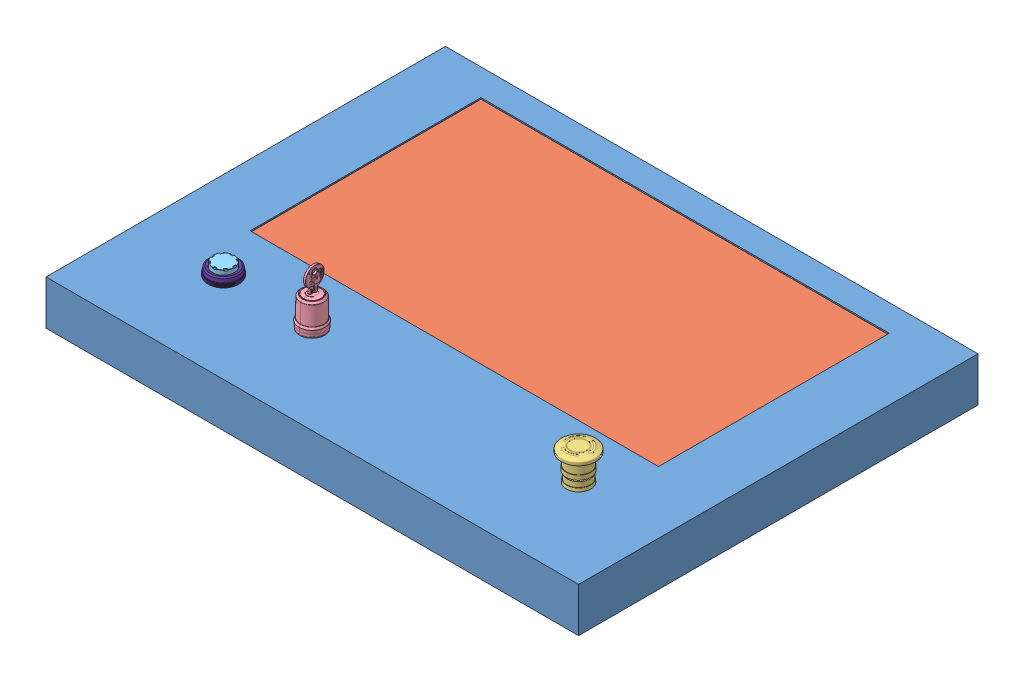
SolidWorks assembly tu dien - Sao chép, configuration Default. Lengths in mm.
Overall size (600 118.01 450).
24 component instances, 23 part files, 9 mates.
Components (placement in the parent):
- bat man hinh-1: bat man hinh [Default] at (221.8904 179.7546 -61.13) x (1 0 0) z (0 1 0) size (600 450 50)
- man hinh-1: man hinh [Default] at (221.8904 208.2546 -126.13) x (1 0 0) z (0 1 0) size (500 300 20)
- User Library-E Stop Button-1: User Library-E Stop Button [Default] at (421.8904 241.2546 63.87) size (39 70.54 39)
- G_IC03_XX_28762V-1: G_IC03_XX_28762V [Default] at (121.8933 229.7546 64.07) x (-0.999896 0 0.014408) z (0.014408 0 0.999896) size (29.48 86.4 29.48)
- dr30e3l-l3gzc-1: dr30e3l-l3gzc [Default] at (23.1032 185.1546 64.858) x (0.429366 0 0.903131) z (0 1 0) size (41 40.2 73.47)
  - dr30e3l-l3gzc_01-1: dr30e3l-l3gzc_01 [Default] at origin size (6.6 6.56 0.7)
  - dr30e3l-l3gzc_02-1: dr30e3l-l3gzc_02 [Default] at origin size (7.7 7.7 1.5)
  - dr30e3l-l3gzc_03-1: dr30e3l-l3gzc_03 [Default] at origin size (39 39 1.5)
  - dr30e3l-l3gzc_04-1: dr30e3l-l3gzc_04 [Default] at origin size (9.1 7.7 3)
  - dr30e3l-l3gzc_05-1: dr30e3l-l3gzc_05 [Default] at origin size (39 39 1.5)
  - dr30e3l-l3gzc_06-1: dr30e3l-l3gzc_06 [Default] at origin size (7.7 7.7 1.5)
  - dr30e3l-l3gzc_07-1: dr30e3l-l3gzc_07 [Default] at origin size (9.1 7.7 3)
  - dr30e3l-l3gzc_08-1: dr30e3l-l3gzc_08 [Default] at origin size (6.6 6.56 0.7)
  - dr30e3l-l3gzc_09-1: dr30e3l-l3gzc_09 [Default] at origin size (7.54 7.17 9.3)
  - dr30e3l-l3gzc_10-1: dr30e3l-l3gzc_10 [Default] at origin size (18.4 29 8.21)
  - dr30e3l-l3gzc_11-1: dr30e3l-l3gzc_11 [Default] at origin size (10 10.77 19.53)
  - dr30e3l-l3gzc_12-1: dr30e3l-l3gzc_12 [Default] at origin size (41 40.2 27.4)
  - dr30e3l-l3gzc_13-1: dr30e3l-l3gzc_13 [Default] at origin size (35 35 10)
  - dr30e3l-l3gzc_14-1: dr30e3l-l3gzc_14 [Default] at origin size (39 39 1.5)
  - dr30e3l-l3gzc_15-1: dr30e3l-l3gzc_15 [Default] at origin size (6.5 6.5 9.3)
  - dr30e3l-l3gzc_16-1: dr30e3l-l3gzc_16 [Default] at origin size (19.8 29.9 44.3)
  - dr30e3l-l3gzc_17-1: dr30e3l-l3gzc_17 [Default] at origin size (26.07 30 22.8)
  - dr30e3l-l3gzc_18-1: dr30e3l-l3gzc_18 [Default] at origin size (39 39 1.5)
  - dr30e3l-l3gzc_19-1: dr30e3l-l3gzc_19 [Default] at origin size (29.15 29.06 9.16)
Mates (geometry in assembly coordinates):
- Coincident10: coincident anti-aligned: plane of bat man hinh-1 through (221.8904 228.2546 -61.13) normal (0 -1 0); plane of man hinh-1 through (221.8904 228.2546 -126.13) normal (0 1 0)
- Coincident13: coincident: plane of bat man hinh-1 through (-8.1096 179.7536 -256.13) normal (0 0 1); line of man hinh-1 through (451.8904 228.2546 -256.13) axis (-1 0 0)
- Coincident14: coincident: plane of bat man hinh-1 through (-8.1096 179.7536 -256.13) normal (1 0 0); line of man hinh-1 through (-8.1096 228.2546 -256.13) axis (0 0 1)
- Concentric6: concentric anti-aligned: cylinder of bat man hinh-1 through (421.8904 179.7536 63.87) axis (0 1 0) radius 11; cylinder of User Library-E Stop Button-1 through (421.8904 228.2546 63.87) axis (0 -1 0) radius 13
- Coincident21: coincident anti-aligned: plane of bat man hinh-1 through (221.8904 228.2546 -61.13) normal (0 -1 0); plane of User Library-E Stop Button-1 through (439.3904 228.2546 78.37) normal (0 1 0)
- Concentric7: concentric anti-aligned: cylinder of bat man hinh-1 through (121.8904 179.7536 63.87) axis (0 1 0) radius 11; cylinder of G_IC03_XX_28762V-1 through (121.8904 203.5546 63.87) axis (0 -1 0) radius 9.8
- Coincident22: coincident anti-aligned: plane of bat man hinh-1 through (221.8904 229.7546 -61.13) normal (0 1 0); plane of G_IC03_XX_28762V-1 through (122.0691 229.7546 76.2688) normal (0 -1 0)
- Concentric8: concentric aligned: cylinder of bat man hinh-1 through (21.8904 179.7536 63.87) axis (0 1 0) radius 11; cylinder of dr30e3l-l3gzc-1/dr30e3l-l3gzc_19-1 through (21.8904 240.0546 63.87) axis (0 1 0) radius 12
- Coincident23: coincident aligned: plane of bat man hinh-1 through (221.8904 229.7546 -61.13) normal (0 1 0); plane of dr30e3l-l3gzc-1/dr30e3l-l3gzc_18-1 through (21.8904 229.7546 63.87) normal (0 1 0)
